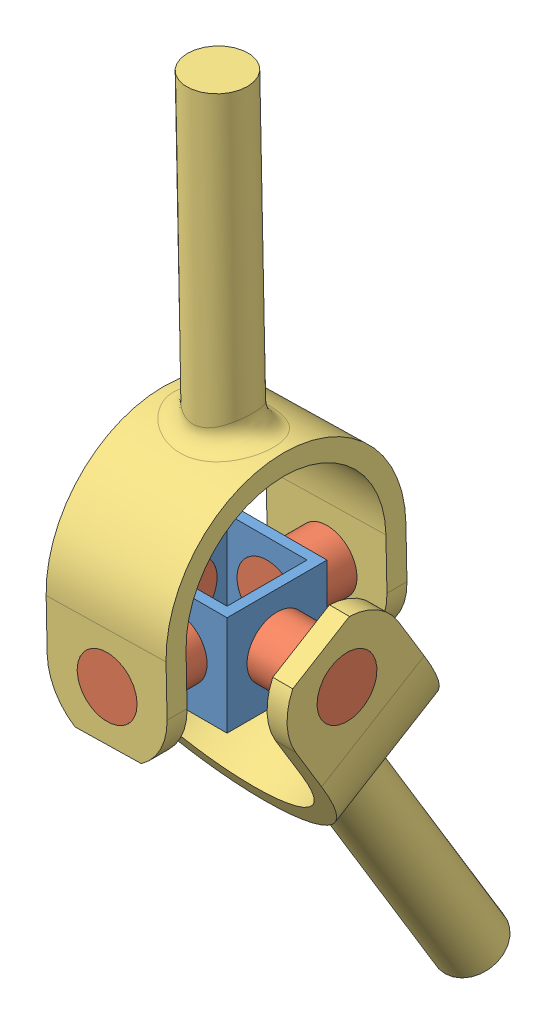
SolidWorks assembly E54, configuration Predeterminado. Lengths in mm.
Overall size (120 452.06 207.5).
7 component instances, 3 part files, 13 mates.
Components (placement in the parent):
- P54.1-1: P54.1 [Predeterminado] at origin size (50 50 50)
- P54.2-1: P54.2 [Predeterminado] at (0 25 60) x (1 0 0) z (0 1 0) size (30 40 30)
- P54.3-1: P54.3 [Predeterminado] at (0 -175.9448 -121.8449) x (1 0 0) z (0 -0.518489 0.855084) size (120 260 60)
- P54.2-2: P54.2 [Predeterminado] at (20 25 0) x (0 -0.531123 0.847295) z (0 0.847295 0.531123) size (30 40 30)
- P54.2-3: P54.2 [Predeterminado] at (-60 25 0) x (0 -0.248323 -0.968677) z (0 -0.968677 0.248323) size (30 40 30)
- P54.2-4: P54.2 [Predeterminado] at (0 25 -20) x (0.997235 -0.07431 0) z (0.07431 0.997235 0) size (30 40 30)
- P54.3-2: P54.3 [Predeterminado] at (-4.797 259.951 0) x (0 0 -1) z (-0.999792 -0.020413 0) size (120 260 60)
Mates (geometry in assembly coordinates):
- Coincidente1: coordinate: point of P54.1-1
- Concéntrica1: concentric anti-aligned: cylinder of P54.1-1 through (0 25 25) axis (0 0 -1) radius 15; cylinder of P54.2-1 through (0 25 20) axis (0 0 1) radius 15
- Coincidente2: coincident aligned: circle of P54.1-1; circle of P54.2-1
- Concéntrica3: concentric anti-aligned: cylinder of P54.1-1 through (-25 25 0) axis (1 0 0) radius 15; cylinder of P54.2-2 through (60 25 0) axis (-1 0 0) radius 15
- Coincidente3: coincident anti-aligned: circle of P54.1-1; circle of P54.2-2
- Concéntrica4: concentric anti-aligned: cylinder of P54.1-1 through (-25 25 0) axis (1 0 0) radius 15; cylinder of P54.2-3 through (-20 25 0) axis (-1 0 0) radius 15
- Coincidente4: coincident aligned: plane of P54.1-1; plane of P54.2-3 through (-20 25 0) normal (1 0 0)
- Concéntrica5: concentric anti-aligned: cylinder of P54.1-1 through (0 25 25) axis (0 0 -1) radius 15; cylinder of P54.2-4 through (0 25 -60) axis (0 0 1) radius 15
- Coincidente5: coincident anti-aligned: circle of P54.1-1; circle of P54.2-4
- Concéntrica6: concentric anti-aligned: cylinder of P54.3-1 through (-60 25 0) axis (1 0 0) radius 15; cylinder of P54.2-3 through (-20 25 0) axis (-1 0 0) radius 15
- Coincidente6: coincident aligned: circle of P54.3-1; circle of P54.2-3
- Concéntrica7: concentric anti-aligned: cylinder of P54.2-1 through (0 25 20) axis (0 0 1) radius 15; cylinder of P54.3-2 through (0 25 60) axis (0 0 -1) radius 15
- Coincidente7: coincident aligned: circle of P54.2-1; circle of P54.3-2
